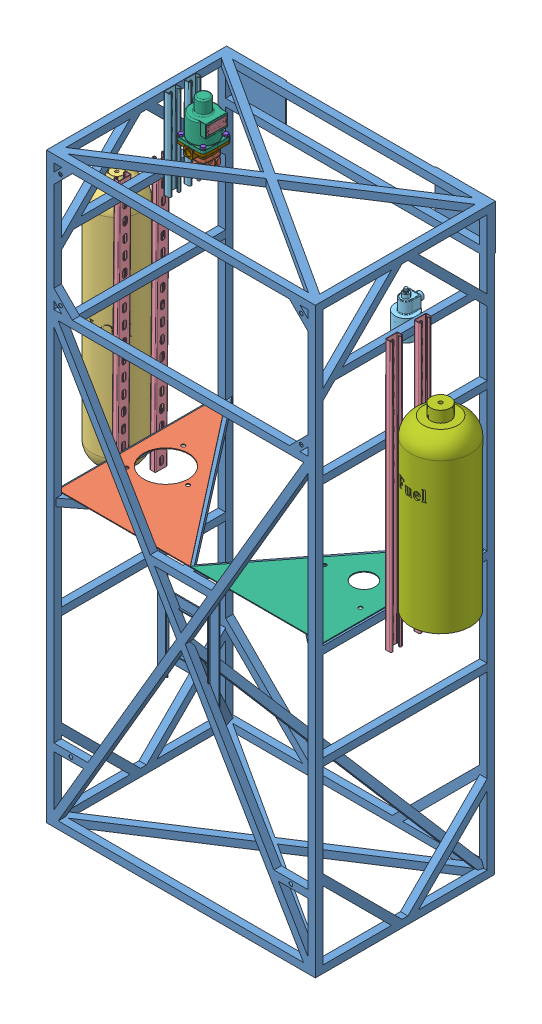
SolidWorks assembly Assm_V.1, configuration Default. Lengths in mm.
Overall size (1329.48 1981.2 612.78).
47 component instances, 25 part files, 13 mates.
Components (placement in the parent):
- 1 Structure-1: 1 Structure [Default<As Machined>] at (-284.1176 -196.1185 283.165) size (914.4 1981.2 612.78)
- LOX Tank base plate-1: LOX Tank base plate [Default] at (-734.9676 -218.8616 556.215) x (0 0 -1) z (-1 0 0) size (546.1 2.66 450.85)
- LOX cylinder1-1: LOX cylinder1 [Default] at (-836.2704 85.0318 253.8396) x (0.893271 0 -0.449518) z (0.449518 0 0.893271) size (168.28 863.6 168.28)
- 3310T347_STRUT CHANNEL-1: 3310T347_STRUT CHANNEL [3310T347] at (-741.3176 573.366 189.2134) x (1 0 0) z (0 0.999962 -0.008727) size (20.64 41.27 914.4)
- 3310T347_STRUT CHANNEL-2: 3310T347_STRUT CHANNEL [3310T347] at (-741.3176 578.2216 319.1882) x (1 0 0) z (0 0.999962 -0.008727) size (20.64 41.27 914.4)
- 3310T310_STRUT CHANNEL 1 ft-4: 3310T310_STRUT CHANNEL 1 ft [3310T31] at (-715.9176 489.0061 126.3892) x (-1 0 0) z (0 -1 0.000903) size (20.64 41.27 304.8)
- 3310T310_STRUT CHANNEL 1 ft-5: 3310T310_STRUT CHANNEL 1 ft [3310T31] at (-715.9176 489.386 194.5481) x (-1 0 0) z (0 -1 0.000903) size (20.64 41.27 304.8)
- E29LR62SC-GDTZCY-2: E29LR62SC-GDTZCY [Default] at (-637.6532 663.6555 157.8275) x (0.008727 0 -0.999962) z (0.999962 0 0.008727) size (101.44 233.26 98.1)
  - BV-F29DC-SLR2SC-Z-1: BV-F29DC-SLR2SC-Z [Default] at origin size (101.44 233.26 98.1)
    - CUP-F25-37RDC-SL-1: CUP-F25-37RDC-SL [Default] at origin size (96.84 129.38 96.84)
      - CUP-F25-37RDC-1: CUP-F25-37RDC [Default] at origin size (96.84 129.38 96.84)
        - CASTING-1544-1: CASTING-1544 [Default] at origin size (96.84 129.38 96.84)
      - SLEEVE-33-1: SLEEVE-33 [Default] at (0 46.0756 0) size (31.75 38.89 31.75)
    - BOLT-50SS-1: BOLT-50SS [Default] at (-38.1661 4.7625 38.1661) x (0 -1 0) z (0.707107 0 0.707107) size (25.7 16.5 14.29)
    - BASE-F29DC-SL-1: BASE-F29DC-SL [Default] at (0 -15.0812 0) size (100.81 59.66 96.84)
      - BASE-F29DC-1: BASE-F29DC [Default] at origin size (100.81 30.18 96.84)
      - SLEEVE-33-1: SLEEVE-33 [Default] at (0 44.5707 0) x (-1 0 0) z (0 0 1) size (31.75 38.89 31.75)
    - STOP-33RDC-1: STOP-33RDC [Default] at (0 -30.6832 0) size (28.57 42.06 28.57)
    - PLUNGER-33RDC-1: PLUNGER-33RDC [Default] at (0 23.0378 0) size (23.29 76.99 23.02)
    - BA-F33R2-3-1: BA-F33R2-3 [Default] at (0 100.0252 0) size (48.34 146.08 48.34)
      - BLB-10-1: BLB-10 [Default] at origin size (25.4 134.16 25.4)
        - BLB-ASM10-1: BLB-ASM10 [Default] at origin size (25.4 134.16 25.4)
          - BS-18-33R-1: BS-18-33R [Default] at origin size (25.4 12.7 25.4)
          - BT-33R-SM-1: BT-33R-SM [Default] at (0 -121.4628 0) size (25.4 126.21 25.4)
          - RNG18COP-1: RNG18COP [Default] at (0 -0.5842 0) size (24.13 1.07 24.12)
      - BB-18-33FR2-3-1: BB-18-33FR2-3 [Default] at (0 -134.1628 0) size (48.34 15.88 48.34)
        - FORGING-2522-1: FORGING-2522 [Default] at origin size (48.34 15.88 48.34)
      - RNGSIL18-33-1: RNGSIL18-33 [Default] at (0 -120.9548 0) size (24.13 1.07 24.12)
    - CB-DC-1: CB-DC [Default] at (0 74.6506 0) size (45.32 17.63 42.82)
    - GASKET-23-T-1: GASKET-23-T [Default] at (0 -34.1439 0) size (48.42 0.79 48.42)
    - BOLT-40SS-1: BOLT-40SS [Default] at (-23.5732 -33.6328 23.5732) x (0 1 0) z (0.707107 0 0.707107) size (31.22 14.66 12.7)
    - VB-SLR2SC-1: VB-SLR2SC [Default] at (0 -76.0984 0) size (84.14 73.02 66.68)
      - VB-SL2SC-1: VB-SL2SC [Default] at origin size (84.14 73.02 66.68)
    - BOLT-40SS-2: BOLT-40SS [Default] at (23.5732 -33.6328 23.5732) x (0 1 0) z (0.707107 0 -0.707107) size (31.22 14.66 12.7)
    - BOLT-40SS-3: BOLT-40SS [Default] at (23.5732 -33.6328 -23.5732) x (0 1 0) z (-0.707107 0 -0.707107) size (31.22 14.66 12.7)
    - BOLT-40SS-4: BOLT-40SS [Default] at (-23.5732 -33.6328 -23.5732) x (0 1 0) z (-0.707107 0 0.707107) size (31.22 14.66 12.7)
    - BOLT-50SS-2: BOLT-50SS [Default] at (38.1661 4.7625 38.1661) x (0 -1 0) z (0.707107 0 -0.707107) size (25.7 16.5 14.29)
    - BOLT-50SS-3: BOLT-50SS [Default] at (38.1661 4.7625 -38.1661) x (0 -1 0) z (-0.707107 0 -0.707107) size (25.7 16.5 14.29)
    - BOLT-50SS-4: BOLT-50SS [Default] at (-38.1661 4.7625 -38.1661) x (0 -1 0) z (-0.707107 0 0.707107) size (25.7 16.5 14.29)
    - SCREW-NP-1: SCREW-NP [Default] at (-31.75 61.9125 46.0375) size (6.86 6.88 8.81)
    - SCREW-NP-2: SCREW-NP [Default] at (31.75 61.9125 46.0375) size (6.86 6.88 8.81)
  - NP-D-1: NP-D [Default] at (0 61.9125 45.2437) size (69.85 30.18 0.64)
- EH40-2-1: EH40-2 [Default] at (106.8941 489.1848 213.4413) x (-0.017452 0 0.999848) z (-0.999848 0 -0.017452) size (87.5 136.65 74.93)
- Fuel tank Base plate-1: Fuel tank Base plate [Default] at (166.7324 -221.5185 556.215) x (0 0 -1) z (1 0 0) size (546.1 2.66 450.85)
- Aluminum fuel tank-2: Aluminum fuel tank [OXYGEN TANK] at (278.6351 -208.626 267.6391) size (203.2 609.6 203.2)
- 3310T347_STRUT CHANNEL-3: 3310T347_STRUT CHANNEL [3310T347] at (173.0824 576.9322 329.8479) x (-1 0 0) z (0 1 -0.000903) size (20.64 41.27 914.4)
- 3310T347_STRUT CHANNEL-4: 3310T347_STRUT CHANNEL [3310T347] at (173.0824 583.7088 232.476) x (-1 0 0) z (0 1 -0.000903) size (20.64 41.27 914.4)
Mates (geometry in assembly coordinates):
- Coincident1: coincident anti-aligned: plane of 1 Structure-1 through (-741.3176 -221.5185 -499716.835) normal (0 1 0); plane of LOX Tank base plate-1 through (-734.9676 -221.5185 556.215) normal (0 -1 0)
- Distance2: distance = 6.35 mm: plane of LOX Tank base plate-1 through (-734.9676 -221.5185 556.215) normal (-1 0 0); line of 1 Structure-1 through (-741.3176 -221.5185 3.765) axis (0 0 1)
- Distance3: distance = 6.35 mm anti-aligned: plane of LOX Tank base plate-1 through (-284.1176 -221.5185 556.215) normal (0 0 1); plane of 1 Structure-1 through (-741.3176 499803.8815 562.565) normal (0 0 -1)
- Coincident7: coincident anti-aligned: plane of 1 Structure-1 through (-741.3176 794.4815 -24.81) normal (-1 0 0); plane of 3310T347_STRUT CHANNEL-1 through (-741.3176 -341.1491 180.0168) normal (1 0 0)
- Coincident8: coincident anti-aligned: plane of 1 Structure-1 through (-741.3176 794.4815 -24.81) normal (-1 0 0); plane of 3310T347_STRUT CHANNEL-2 through (-741.3176 -336.2934 309.9916) normal (1 0 0)
- Coincident9: coincident: plane of 1 Structure-1 through (-741.3176 794.4815 -24.81) normal (-1 0 0); plane of ? through (-741.3176 647.0112 -22.7561) normal (1 0 0)
- Coincident10: coincident anti-aligned: plane of 1 Structure-1 through (-741.3176 794.4815 -24.81) normal (-1 0 0); plane of ? through (-741.3176 709.3447 -21.1009) normal (1 0 0)
- Coincident12: coincident anti-aligned: plane of 1 Structure-1 through (-715.9176 794.4815 562.565) normal (1 0 0); plane of 3310T310_STRUT CHANNEL 1 ft-4 through (-715.9176 793.7904 108.9373) normal (-1 0 0)
- Coincident15: coincident anti-aligned: plane of 1 Structure-1 through (-741.3176 -221.5185 -499716.835) normal (0 1 0); plane of Fuel tank Base plate-1 through (166.7324 -221.5185 556.215) normal (0 -1 0)
- Distance4: distance = 6.35 mm aligned: plane of Fuel tank Base plate-1 through (166.7324 -218.8616 556.215) normal (1 0 0); plane of 1 Structure-1 through (173.0824 794.4815 -21.635) normal (1 0 0)
- Distance5: distance = 6.35 mm anti-aligned: plane of Fuel tank Base plate-1 through (-284.1176 -218.8616 556.215) normal (0 0 1); plane of 1 Structure-1 through (-741.3176 499803.8815 562.565) normal (0 0 -1)
- Coincident19: coincident anti-aligned: plane of 1 Structure-1 through (173.0824 794.4815 -21.635) normal (1 0 0); plane of 3310T347_STRUT CHANNEL-3 through (173.0824 -337.4519 347.8501) normal (-1 0 0)
- Coincident20: coincident anti-aligned: plane of 1 Structure-1 through (173.0824 794.4815 -21.635) normal (1 0 0); plane of 3310T347_STRUT CHANNEL-4 through (173.0824 -330.6753 250.4781) normal (-1 0 0)
